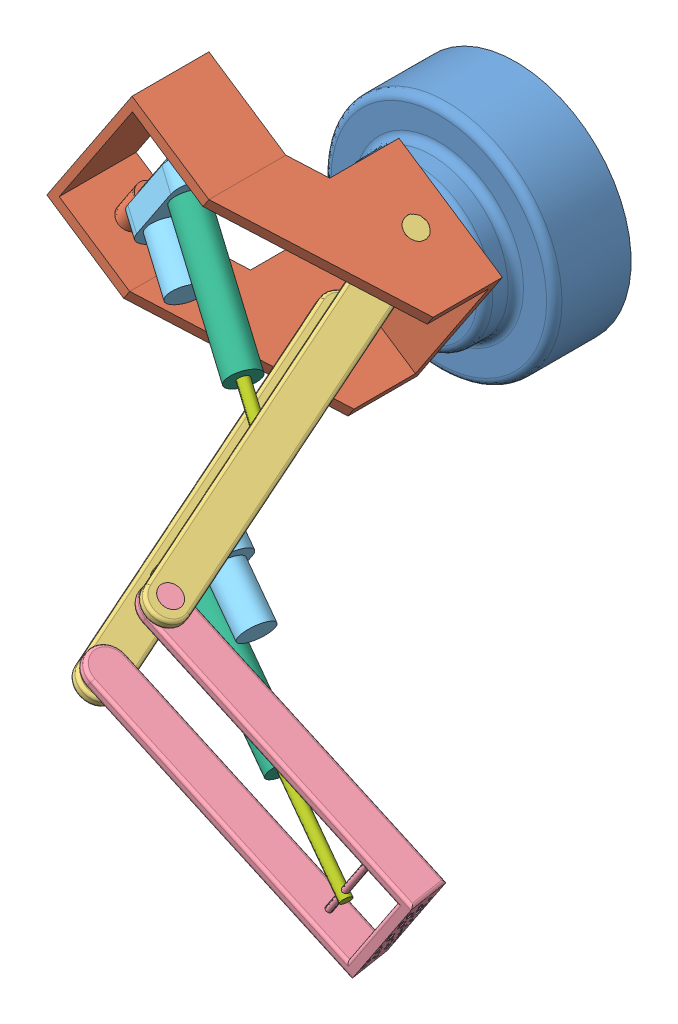
SolidWorks assembly finish 1, configuration Default. Lengths in mm.
Overall size (378.61 294.95 341.45).
10 component instances, 7 part files, 18 mates.
Components (placement in the parent):
- np2-2: np2 [Default] at (-105.9015 111.1219 -48.6119) size (150 150 85)
- Part1-2: Part1 [Default] at (-202.4877 173.5524 119.0843) x (0.553752 0.832682 0) z (-0.832682 0.553752 0) size (100.07 107.16 160.36)
- np3-1: np3 [Default] at (-44.0964 121.6605 160.2627) x (0.303951 -0.202134 0.930997) z (-0.553752 -0.832682 0) size (275 25 100)
- np4-1: np4 [Default] at (61.82 42.8172 264.4817) x (0.826633 -0.549729 -0.120313) z (-0.553752 -0.832682 0) size (194.5 25 86)
- asnp1-2: asnp1 [Default] at (-177.6841 158.7731 105.1534) x (-0.553752 -0.832682 0) z (0.768219 -0.510883 0.385796) size (65 25 58.32)
- np5-2: np5 [Default] at (-162.8574 164.4076 109.0113) x (-0.17439 0.412842 0.893952) z (0.768219 -0.510883 0.385796) size (20 20 98)
- np6-2: np6 [Default] at (-57.8307 94.5625 161.7552) x (-0.553752 -0.832682 0) z (-0.768219 0.510883 -0.385796) size (15 15 120)
- asnp1-3: asnp1 [Default] at (-46.6071 71.6898 216.1646) x (0.553752 0.832682 0) z (0.809579 -0.538388 0.233924) size (65 25 58.32)
- np5-3: np5 [Default] at (-45.6558 55.5626 218.5038) x (0.582813 0.689637 -0.429801) z (0.809579 -0.538388 0.233924) size (20 20 98)
- np6-3: np6 [Default] at (90.2272 -34.8026 257.7667) x (0.553752 0.832682 0) z (-0.809579 0.538388 -0.233924) size (15 15 120)
Mates (geometry in assembly coordinates):
- Coincident4: coincident anti-aligned: plane of Part1-2 through (-177.8458 210.6068 119.0843) normal (-0.553752 -0.832682 0); plane of np3-1 through (-44.0964 121.6605 160.2627) normal (0.553752 0.832682 0)
- Coincident5: coincident anti-aligned: plane of np3-1 through (-85.9665 141.0984 43.8881) normal (-0.553752 -0.832682 0); plane of np4-1 through (141.1891 -9.965 265.5213) normal (0.553752 0.832682 0)
- Concentric4: concentric aligned: cylinder of np3-1 through (-6.6342 96.7473 275.0091) axis (-0.553752 -0.832682 0) radius 7; cylinder of np4-1 through (-6.6342 96.7473 275.0091) axis (-0.553752 -0.832682 0) radius 7
- Concentric17: concentric anti-aligned: cylinder of np2-2 through (-105.9015 111.1219 36.3881) axis (0 0 -1) radius 15; cylinder of Part1-2 through (-105.9015 111.1219 21.3881) axis (0 0 1) radius 15
- Coincident22: coincident anti-aligned: plane of np2-2 through (-105.9015 111.1219 21.3881) normal (0 0 1); plane of Part1-2 through (-202.4877 173.5524 21.3881) normal (0 0 -1)
- Concentric18: concentric anti-aligned: cylinder of Part1-2 through (-78.2139 152.756 43.8881) axis (-0.553752 -0.832682 0) radius 7; cylinder of np3-1 through (-133.5891 69.4878 43.8881) axis (0.553752 0.832682 0) radius 7
- Concentric23: concentric anti-aligned: cylinder of Part1-2 through (-208.5672 119.2641 103.5486) axis (0.553752 0.832682 0) radius 2.25; cylinder of asnp1-2 through (-169.8046 177.5518 103.5486) axis (-0.553752 -0.832682 0) radius 2.25
- Concentric24: concentric aligned: cylinder of np5-2 through (-91.413 116.8955 144.8904) axis (0.768219 -0.510883 0.385796) radius 3.5; cylinder of np6-2 through (-134.6526 145.6508 123.1756) axis (0.768219 -0.510883 0.385796) radius 3.5
- LimitDistance8: limit distance = 56.2855 mm anti-aligned: plane of np6-2 through (-134.6526 145.6508 123.1756) normal (0.768219 -0.510883 0.385796); plane of np5-2 through (-91.413 116.8955 144.8904) normal (-0.768219 0.510883 -0.385796)
- Coincident30: coincident aligned: circle of asnp1-2; circle of np5-2
- Concentric25: concentric anti-aligned: cylinder of np3-1 through (-89.504 53.3806 160.2627) axis (0.553752 0.832682 0) radius 2; cylinder of np6-2 through (-56.6496 102.7841 160.2627) axis (-0.553752 -0.832682 0) radius 2
- Concentric27: concentric aligned: cylinder of np5-3 through (29.635 5.4925 240.2588) axis (0.809579 -0.538388 0.233924) radius 3.5; cylinder of np6-3 through (9.2693 19.0362 234.3742) axis (0.809579 -0.538388 0.233924) radius 3.5
- LimitDistance9: limit distance = 25.1559 mm anti-aligned: plane of np6-3 through (9.2693 19.0362 234.3742) normal (0.809579 -0.538388 0.233924); plane of np5-3 through (29.635 5.4925 240.2588) normal (-0.809579 0.538388 -0.233924)
- Coincident32: coincident aligned: circle of asnp1-3; circle of np5-3
- Concentric28: concentric aligned: cylinder of np3-1 through (-71.5709 41.4547 215.1916) axis (0.553752 0.832682 0) radius 2.25; cylinder of asnp1-3 through (-61.0497 57.2756 215.1916) axis (0.553752 0.832682 0) radius 2.25
- Concentric29: concentric anti-aligned: cylinder of np4-1 through (111.9598 4.6693 256.8617) axis (-0.553752 -0.832682 0) radius 2; cylinder of np6-3 through (82.9421 -38.9649 256.8617) axis (0.553752 0.832682 0) radius 2
- Coincident36: coincident anti-aligned: plane of Part1-2 through (-169.8046 177.5518 103.5486) normal (-0.553752 -0.832682 0); plane of asnp1-2 through (-167.6045 176.0887 104.6535) normal (0.553752 0.832682 0)
- Coincident38: coincident anti-aligned: plane of np3-1 through (-39.1654 90.7597 214.3774) normal (-0.553752 -0.832682 0); plane of asnp1-3 through (-36.5811 89.0411 215.8615) normal (0.553752 0.832682 0)
